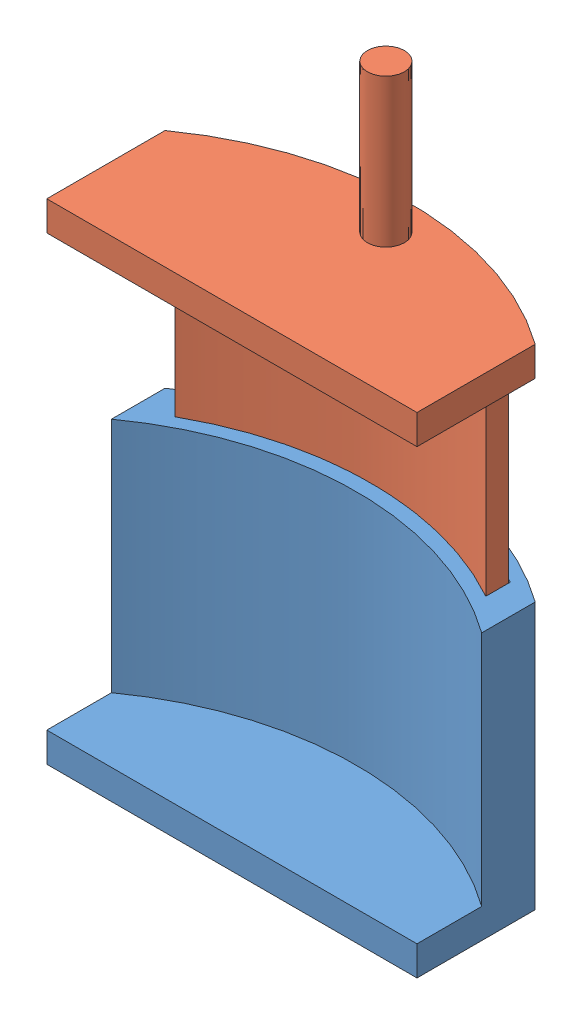
SolidWorks assembly ClampAssembly, configuration Default. Lengths in mm.
Overall size (31.75 54.7 15.24).
2 component instances, 2 part files, 4 mates.
Components (placement in the parent):
- Clamp-Bottom-2: Clamp-Bottom [Default] at origin size (31.75 22.86 15.24)
- Clamp-Top-2: Clamp-Top [Default] at (31.75 42.0023 0) x (-1 0 0) z (0 0 1) size (31.75 40.64 15.24)
Mates (geometry in assembly coordinates):
- Coincident4: coincident anti-aligned: plane of Clamp-Bottom-2 through (29.21 22.86 -27.0547) normal (-1 0 0); plane of Clamp-Top-2 through (29.21 14.0623 -26.9117) normal (1 0 0)
- Coincident6: coincident anti-aligned: plane of Clamp-Bottom-2 through (2.54 22.86 -26.9117) normal (1 0 0); plane of Clamp-Top-2 through (2.54 14.0623 -27.0547) normal (-1 0 0)
- Parallel3: parallel anti-aligned: cylinder of Clamp-Bottom-2 through (16.002 22.86 -3.302) axis (0 -1 0) radius 27.178; cylinder of Clamp-Top-2 through (15.748 14.0623 -3.302) axis (0 1 0) radius 27.178
- Concentric6: concentric anti-aligned: cylinder of Clamp-Bottom-2 through (15.875 22.86 -1.27) axis (0 -1 0) radius 27.178; cylinder of Clamp-Top-2 through (15.875 14.0623 -1.27) axis (0 1 0) radius 27.178
